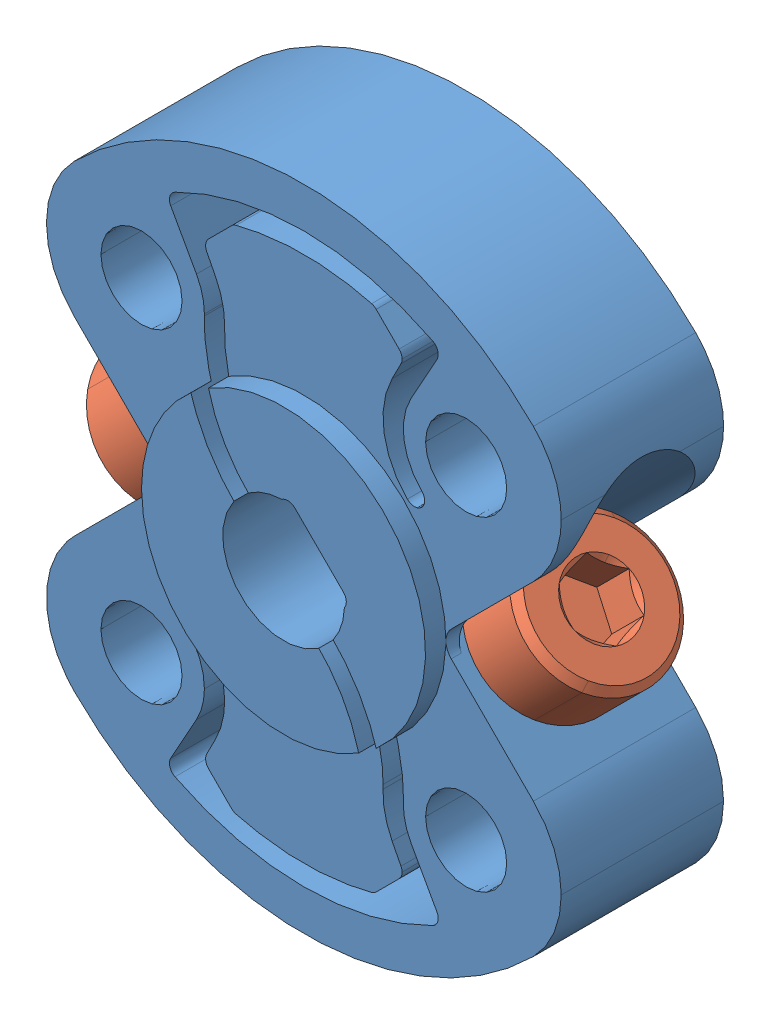
SolidWorks assembly 6mm Thru-hole D-shaft 1311-0016-1006, configuration Default. Lengths in mm.
Overall size (28.36 32 9.95).
3 component instances, 2 part files, 0 mates.
Components (placement in the parent):
- 1311-0016-1006.STEP-1: 1311-0016-1006.STEP [Default] at (-31.225 1.9638 14.6428) size (25.38 32 9)
- 2800-0004-0014_90128A207.STEP-1: 2800-0004-0014_90128A207.STEP [Default] at (-33.2778 -9.1549 14.6428) x (0.5 -0.5 0.707107) z (-0.707107 -0.707107 0) size (7 7 18.01)
- 2800-0004-0014_90128A207.STEP-2: 2800-0004-0014_90128A207.STEP [Default] at (-29.1721 13.0826 14.6428) x (-0.5 0.5 0.707107) z (0.707107 0.707107 0) size (7 7 18.01)
